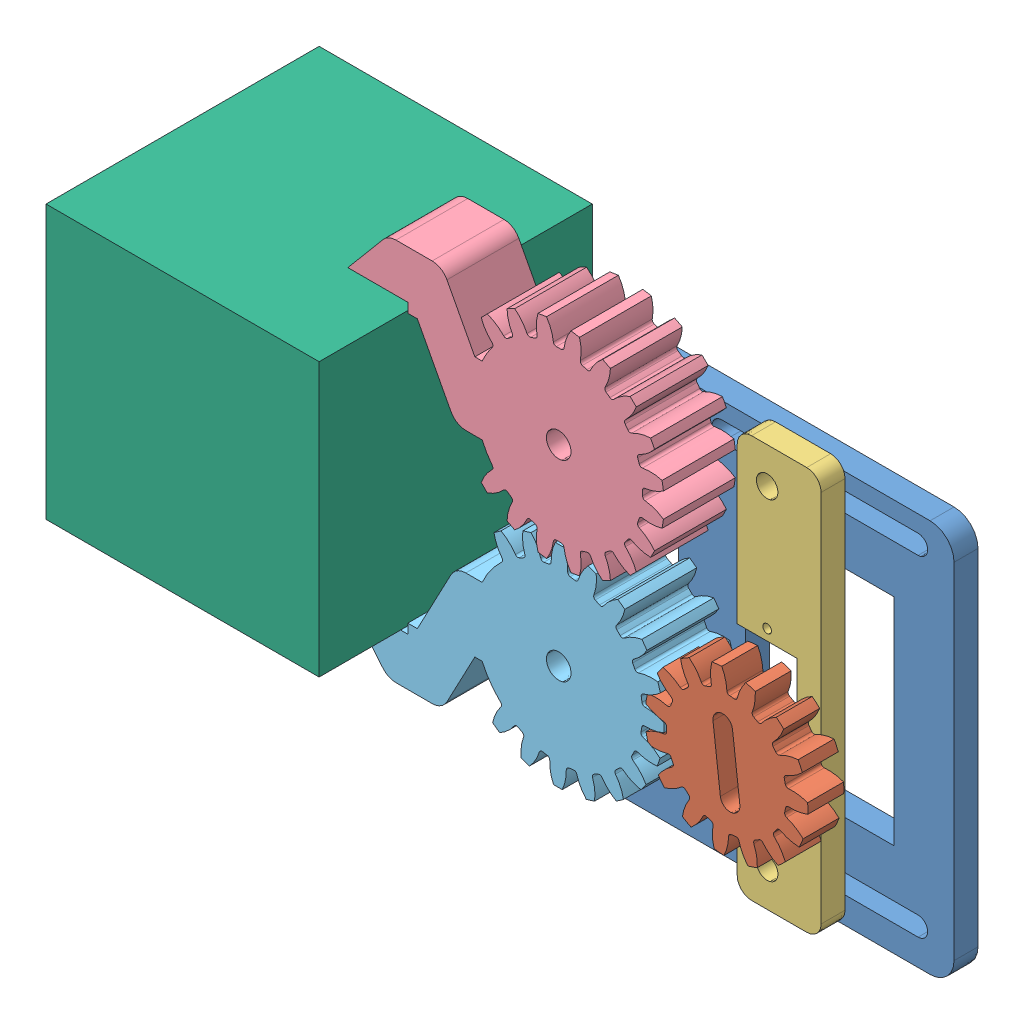
SolidWorks assembly Test Jig, configuration Default. Lengths in mm.
Overall size (156 94.1 57).
14 component instances, 8 part files, 36 mates.
Components (placement in the parent):
- clasper_testjig-1: clasper_testjig [Default] at (-25.5961 27.0609 -15.2852) size (77.5 82 5)
- Driven_Gears-1: Driven_Gears [Default] at (-25.5961 47.0609 -2.7852) x (0.995088 -0.098999 0) z (0 0 1) size (43.7 43.7 15) (hidden)
- Driving_Gears-1: Driving_Gears [Default] at (9.4039 7.0609 0.9648) x (-0.993016 -0.117978 0) z (0 0 1) size (43 43 7.5)
- Driven_Gears-2: Driven_Gears [Default] at (-25.5961 7.0609 -2.7852) x (0.99881 -0.048773 0) z (0 0 1) size (43.7 43.7 15) (hidden)
- SG90_adapter-1: SG90_adapter [Default] at (7.9082 12.0609 -10.2852) size (22.5 84 5)
- Clasper_A-1: Clasper_A [Default] at (-47.0961 39.9359 -10.2852) size (65.85 43.7 15)
- Clasper_B2-1: Clasper_B2 [Default] at (-47.0961 14.1859 4.7148) x (1 0 0) z (0 0 -1) size (66 44 15)
- HiTorqServo_adapter-1: HiTorqServo_adapter [Default] at (9.4039 17.3109 -10.2852) size (30 84 5) (hidden)
- cube-1: cube [Default] at (-85.5961 -1.4391 -5.2852) size (57 57 57)
- clasper_testjig-2: clasper_testjig [Default] at (-78.0961 27.0609 -65.2852) x (0 0 -1) z (1 0 0) size (77.5 82 5) (hidden)
- Driving_Gears-2: Driving_Gears [Default] at (-86.8461 4.0799 -99.4176) x (0 -0.062178 -0.998065) z (-1 0 0) size (43 43 7.5) (hidden)
- SG90_adapter-2: SG90_adapter [Default] at (-78.0961 22.0609 -121.5352) x (0 0 -1) z (-1 0 0) size (22.5 84 5) (hidden)
- Clasper_B2-5: Clasper_B2 [Default] at (-78.0961 14.1859 -43.7852) x (0 0 -1) z (-1 0 0) size (66 44 15) (hidden)
- Clasper_A-2: Clasper_A [Default] at (-93.0961 39.9359 -43.7852) x (0 0 -1) z (1 0 0) size (65.85 43.7 15) (hidden)
Mates (geometry in assembly coordinates):
- Concentric1: concentric aligned: cylinder of clasper_testjig-1 through (-25.5961 47.0609 -10.2852) axis (0 0 1) radius 2.75; cylinder of Driven_Gears-1 through (-25.5961 47.0609 -10.2852) axis (0 0 1) radius 2.5
- Coincident1: coincident anti-aligned: plane of clasper_testjig-1 through (-25.5961 27.0609 -10.2852) normal (0 0 1); plane of Driven_Gears-1 through (-25.5961 47.0609 -10.2852) normal (0 0 -1)
- Concentric2: concentric: point of clasper_testjig-1; cylinder of Driving_Gears-1 through (9.4039 7.0609 -2.7852) axis (0 0 1) radius 12.5
- Concentric3: concentric aligned: cylinder of clasper_testjig-1 through (-25.5961 7.0609 -10.2852) axis (0 0 1) radius 2.75; cylinder of Driven_Gears-2 through (-25.5961 7.0609 -10.2852) axis (0 0 1) radius 2.5
- Coincident3: coincident anti-aligned: plane of clasper_testjig-1 through (-25.5961 27.0609 -10.2852) normal (0 0 1); plane of Driven_Gears-2 through (-25.5961 7.0609 -10.2852) normal (0 0 -1)
- Coincident4: coincident aligned: plane of Driving_Gears-1 through (9.4039 7.0609 4.7148) normal (0 0 1); plane of Driven_Gears-2 through (-25.5961 7.0609 4.7148) normal (0 0 1)
- Tangent1: tangent anti-aligned: plane of clasper_testjig-1 through (-6.5961 -15.4391 -10.2852) normal (0 -1 0); cylinder of SG90_adapter-1 through (7.9082 -17.6891 -10.2852) axis (0 0 1) radius 2.25
- Coincident5: coincident anti-aligned: plane of clasper_testjig-1 through (-25.5961 27.0609 -10.2852) normal (0 0 1); plane of SG90_adapter-1 through (7.9082 12.0609 -10.2852) normal (0 0 -1)
- Parallel1: parallel aligned: plane of clasper_testjig-1 through (41.9039 -24.9391 -10.2852) normal (1 0 0); plane of SG90_adapter-1 through (19.1582 12.0609 -5.2852) normal (1 0 0)
- Concentric4: concentric aligned: cylinder of clasper_testjig-1 through (-25.5961 47.0609 -10.2852) axis (0 0 1) radius 2.75; cylinder of Clasper_A-1 through (-25.5961 47.0609 -10.2852) axis (0 0 1) radius 2.575
- Coincident8: coincident anti-aligned: plane of clasper_testjig-1 through (-25.5961 27.0609 -10.2852) normal (0 0 1); plane of Clasper_A-1 through (-47.0961 39.9359 -10.2852) normal (0 0 -1)
- Coincident9: coincident anti-aligned: plane of clasper_testjig-1 through (-25.5961 27.0609 -10.2852) normal (0 0 1); plane of Clasper_B2-1 through (-47.0961 14.1859 -10.2852) normal (0 0 -1)
- Concentric5: concentric anti-aligned: circle of clasper_testjig-1; cylinder of Clasper_B2-1 through (-25.5961 7.0609 4.7148) axis (0 0 -1) radius 2.575
- Parallel3: parallel aligned: plane of clasper_testjig-1 through (41.9039 57.0609 -10.2852) normal (0 1 0); plane of Clasper_B2-1 through (-47.0961 -2.9391 -10.2852) normal (0 1 0)
- Parallel4: parallel anti-aligned: plane of Clasper_A-1 through (-47.0961 57.0609 4.7148) normal (0 -1 0); plane of Clasper_B2-1 through (-47.0961 -2.9391 -10.2852) normal (0 1 0)
- Tangent2: tangent anti-aligned: plane of clasper_testjig-1 through (-6.5961 -19.4391 -10.2852) normal (0 1 0); cylinder of HiTorqServo_adapter-1 through (9.4039 -17.1891 -10.2852) axis (0 0 1) radius 2.25
- Parallel5: parallel aligned: plane of clasper_testjig-1 through (41.9039 -24.9391 -10.2852) normal (1 0 0); plane of HiTorqServo_adapter-1 through (24.4039 17.3109 -5.2852) normal (1 0 0)
- Coincident11: coincident anti-aligned: plane of clasper_testjig-1 through (-25.5961 27.0609 -10.2852) normal (0 0 1); plane of HiTorqServo_adapter-1 through (9.4039 17.3109 -10.2852) normal (0 0 -1)
- Width1: width aligned: plane of cube-1 through (-114.0961 55.5609 23.2148) normal (0 0 1); plane of cube-1 through (-114.0961 55.5609 -33.7852) normal (0 0 -1); plane of Clasper_B2-1 through (-47.0961 14.1859 4.7148) normal (0 0 1); plane of clasper_testjig-1 through (-25.5961 27.0609 -15.2852) normal (0 0 -1)
- Width2: width aligned: plane of Clasper_B2-1 through (-47.0961 -2.9391 -10.2852) normal (0 1 0); plane of Clasper_A-1 through (-47.0961 57.0609 4.7148) normal (0 -1 0); plane of cube-1 through (-85.5961 55.5609 -5.2852) normal (0 1 0); plane of cube-1 through (-85.5961 -1.4391 -5.2852) normal (0 -1 0)
- Concentric6: concentric aligned: circle of clasper_testjig-2; circle of Clasper_A-2
- Concentric7: concentric anti-aligned: circle of clasper_testjig-2; circle of Clasper_B2-5
- Coincident12: coincident anti-aligned: plane of clasper_testjig-2 through (-78.0961 27.0609 -65.2852) normal (-1 0 0); plane of Clasper_B2-5 through (-78.0961 14.1859 -43.7852) normal (1 0 0)
- Coincident13: coincident anti-aligned: plane of clasper_testjig-2 through (-78.0961 27.0609 -65.2852) normal (-1 0 0); plane of Clasper_A-2 through (-78.0961 39.9359 -43.7852) normal (1 0 0)
- Parallel6: parallel anti-aligned: plane of Clasper_B2-5 through (-93.0961 -2.9391 -43.7852) normal (0 1 0); plane of Clasper_A-2 through (-78.0961 57.0609 -43.7852) normal (0 -1 0)
- Parallel7: parallel anti-aligned: plane of cube-1 through (-85.5961 -1.4391 -5.2852) normal (0 -1 0); plane of Clasper_B2-5 through (-93.0961 -2.9391 -43.7852) normal (0 1 0)
- Coincident16: coincident aligned: plane of clasper_testjig-1 through (-35.5961 -24.9391 -10.2852) normal (0 -1 0); plane of clasper_testjig-2 through (-73.0961 -24.9391 -55.2852) normal (0 -1 0)
- Tangent3: tangent anti-aligned: cylinder of SG90_adapter-2 through (-78.0961 51.8109 -121.5352) axis (1 0 0) radius 2.25; plane of clasper_testjig-2 through (-73.0961 49.5609 -84.2852) normal (0 1 0)
- Coincident20: coincident aligned: plane of clasper_testjig-2 through (-73.0961 -24.9391 -132.7852) normal (0 0 -1); plane of SG90_adapter-2 through (-83.0961 22.0609 -132.7852) normal (0 0 -1)
- Parallel8: parallel anti-aligned: plane of cube-1 through (-114.0961 55.5609 -33.7852) normal (-1 0 0); plane of clasper_testjig-2 through (-73.0961 27.0609 -65.2852) normal (1 0 0)
- Coincident25: coincident anti-aligned: plane of Driving_Gears-2 through (-83.0961 4.0799 -99.4176) normal (1 0 0); plane of SG90_adapter-2 through (-83.0961 22.0609 -121.5352) normal (-1 0 0)
- Width3: width anti-aligned: plane of cube-1 through (-114.0961 55.5609 -33.7852) normal (-1 0 0); plane of cube-1 through (-57.0961 55.5609 -33.7852) normal (1 0 0); plane of Clasper_A-2 through (-78.0961 39.9359 -43.7852) normal (1 0 0); plane of Clasper_A-2 through (-93.0961 39.9359 -43.7852) normal (-1 0 0)
- Coincident27: coincident anti-aligned: plane of Clasper_B2-1 through (-57.0961 14.1859 -10.2852) normal (-1 0 0); plane of cube-1 through (-57.0961 55.5609 -33.7852) normal (1 0 0)
- Width4: width anti-aligned: plane of Clasper_B2-5 through (-93.0961 -2.9391 -43.7852) normal (0 1 0); plane of Clasper_A-2 through (-78.0961 57.0609 -43.7852) normal (0 -1 0); plane of cube-1 through (-85.5961 -1.4391 -5.2852) normal (0 -1 0); plane of cube-1 through (-85.5961 55.5609 -5.2852) normal (0 1 0)
- Coincident28: coincident anti-aligned: plane of cube-1 through (-114.0961 55.5609 -33.7852) normal (0 0 -1); plane of Clasper_A-2 through (-78.0961 39.9359 -33.7852) normal (0 0 1)
- Coincident29: coincident anti-aligned: plane of clasper_testjig-2 through (-78.0961 27.0609 -65.2852) normal (-1 0 0); plane of SG90_adapter-2 through (-78.0961 22.0609 -121.5352) normal (1 0 0)
